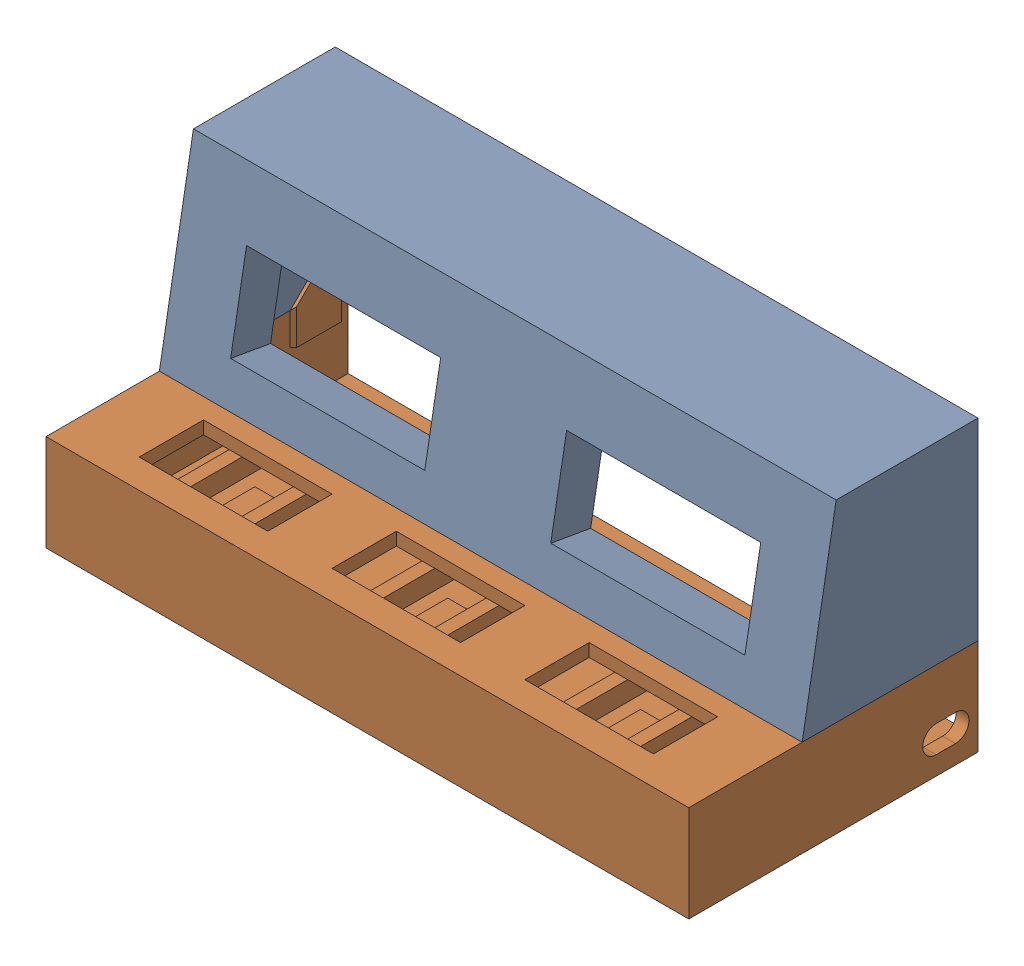
SolidWorks assembly Counter_Assembly, configuration Default. Lengths in mm.
Overall size (100 45 45).
2 component instances, 2 part files, 4 mates.
Components (placement in the parent):
- Counter_Front-1: Counter_Front [Default] at origin size (100 30 27.36)
- Counter_ButtonMount-1: Counter_ButtonMount [Default] at (0 -15 22.5) x (-1 0 0) z (0 0 -1) size (100 19.5 45)
Mates (geometry in assembly coordinates):
- Coincident1: coordinate: point of Counter_Front-1
- Coincident2: coincident aligned: plane of Counter_Front-1 through (-50 -22.5 30) normal (-1 0 0); plane of Counter_ButtonMount-1 through (-50 -15 22.5) normal (-1 0 0)
- Coincident4: coincident aligned: plane of Counter_Front-1 through (0 0 0) normal (0 0 -1); plane of Counter_ButtonMount-1 through (-50 -22.5 0) normal (0 0 -1)
- Coincident5: coincident anti-aligned: plane of Counter_Front-1 through (50 -7.5 0) normal (0 -1 0); plane of Counter_ButtonMount-1 through (-50 -7.5 0) normal (0 1 0)
